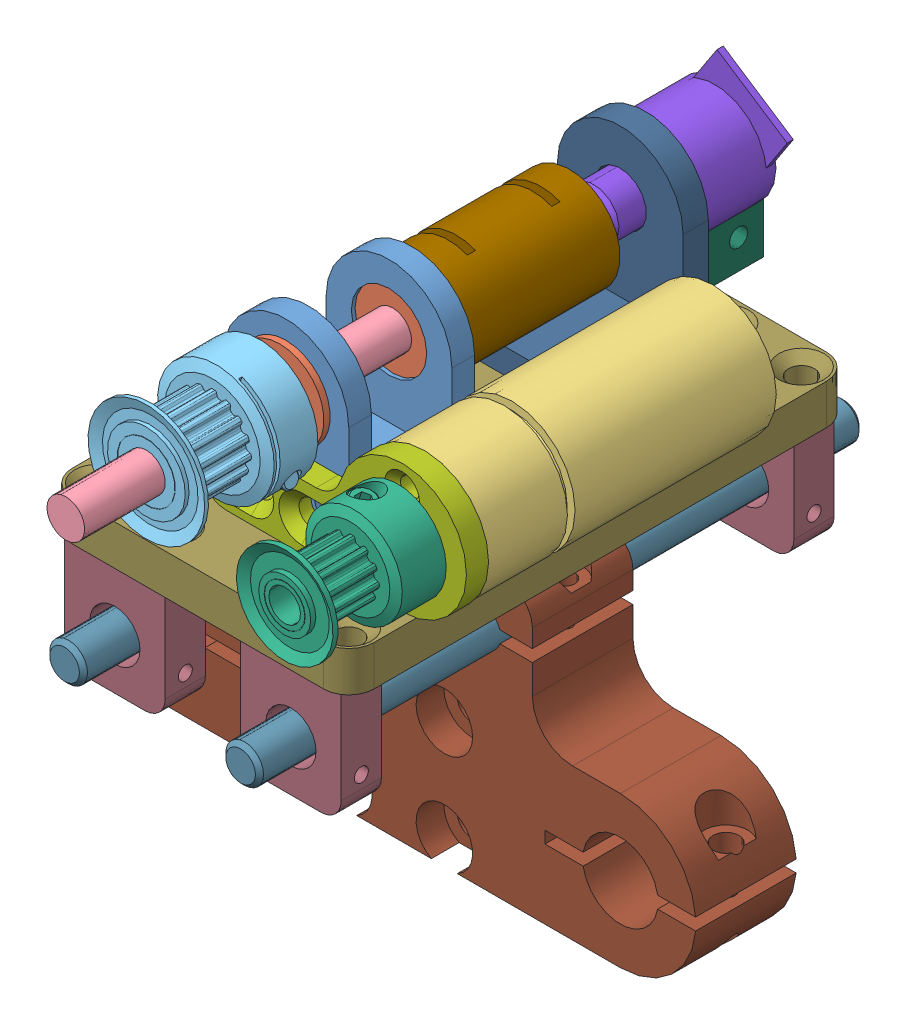
SolidWorks assembly wrist-yaw-joint, configuration Default. Lengths in mm.
Overall size (76.14 66.56 105.58).
22 component instances, 17 part files, 53 mates.
Components (placement in the parent):
- n05-headyoke-1: n05-headyoke [Default] at origin size (15.88 21.91 15.88)
- p1875bearing-57155K319-MCM-1: p1875bearing-57155K319-MCM [Default] at (0 13.97 5.5499) x (0 0 -1) z (0 -1 0) size (3.17 11.18 11.18)
- p1875bearing-57155K319-MCM-2: p1875bearing-57155K319-MCM [Default] at (0 13.97 -5.5499) x (0 0 1) z (0 -1 0) size (3.17 11.18 11.18)
- MAXON-AMAX16-110049-110323-1: MAXON-AMAX16-110049-110323 [Default] at (17.4625 8.128 -28.5125) x (0 0 -1) z (1 0 0) size (48.2 16 16)
- n06-p1875shaft-1: n06-p1875shaft [Default] at (0 13.97 -15.0749) size (4.76 4.76 50.8)
- a_6d16-016df2506-p1875bore-16teeth-1: a_6d16-016df2506-p1875bore-16teeth [Default] at (0 13.97 17.218) x (0.167713 -0.985836 0) z (0 0 -1) size (14.73 14.73 14.29)
- a_6d16m012df6003-3mm-bored-to-4mm-1: a_6d16m012df6003-3mm-bored-to-4mm [Default] at (17.4625 8.128 17.2524) x (-0.948708 0.316155 0) z (0 0 -1) size (12.2 12.2 14.3)
- a_6n16-015df1206-2: a_6n16-015df1206 [Default] at (-14.2838 6.954 15.9813) x (0.986257 0.164531 -0.015045) z (-0.021924 0.040076 -0.998956) size (14.1 14.1 11.13) (hidden)
- n09-motor-holder-1: n09-motor-holder [Default] at (17.4625 8.128 7.9375) size (33.53 16.26 2.79)
- POT-eti-sys-EUP125-1: POT-eti-sys-EUP125 [Default] at (0 13.97 -47.4345) x (0 0 -1) z (0.836462 -0.548026 0) size (30.58 15.39 13)
- 000_helical-coupling-6208K53-MCM-1: 000_helical-coupling-6208K53-MCM [Default] at (0 13.97 -18.3769) size (12.7 12.7 19.05)
- n10-potholder-1: n10-potholder [Default] at (0 0 -29.5148) size (15.88 21.91 15.88)
- w04-shaft-hold-bottom-2: w04-shaft-hold-bottom [Default] at (0 -32.0675 -5.715) x (1 0 0) z (0 1 0) size (76.14 12.7 34.92)
- w06-plate-1: w06-plate [Default] at (0 0 -12.7) x (1 0 0) z (0 -1 0) size (38.1 63.5 5.08)
- w07-clamp-1: w07-clamp [Default] at (11.1125 -13.0175 -43.815) size (12.7 14.29 5.08)
- w07-clamp-2: w07-clamp [Default] at (11.1125 -13.0175 13.335) size (12.7 14.29 5.08)
- w07-clamp-3: w07-clamp [Default] at (-11.1125 -13.0175 -43.815) size (12.7 14.29 5.08)
- w07-clamp-4: w07-clamp [Default] at (-11.1125 -13.0175 13.335) size (12.7 14.29 5.08)
- w08-p1875shaft-1: w08-p1875shaft [Default] at (-11.1125 -13.0175 -51.435) size (4.76 4.76 76.2)
- w08-p1875shaft-2: w08-p1875shaft [Default] at (11.1125 -13.0175 -51.435) size (4.76 4.76 76.2)
- 000_Bourns_linearpot_body_3048seriesRevC-dp2-1: 000_Bourns_linearpot_body_3048seriesRevC-dp2 [Default] at (-23.8125 -10.668 -38.1) x (0 0 -1) z (0 -1 0) size (31.75 6.35 8.28)
- y18-pot-end-holder-1: y18-pot-end-holder [Default] at (-20.6375 -18.8595 -12.065) x (0 0 1) z (-1 0 0) size (10.16 9.53 6.35)
Mates (geometry in assembly coordinates):
- Coincident1: coincident anti-aligned: plane of n05-headyoke-1 through (0 13.97 7.9375) normal (0 0 1); plane of p1875bearing-57155K319-MCM-1 through (4.7625 13.97 7.9375) normal (0 0 -1)
- Coincident2: coincident anti-aligned: plane of n05-headyoke-1 through (0 13.97 -7.9375) normal (0 0 -1); plane of p1875bearing-57155K319-MCM-2 through (-4.7625 13.97 -7.9375) normal (0 0 1)
- Concentric1: concentric anti-aligned: cylinder of n05-headyoke-1; cylinder of p1875bearing-57155K319-MCM-2
- Concentric2: concentric aligned: cylinder of n05-headyoke-1; cylinder of p1875bearing-57155K319-MCM-1
- Coincident3: coincident anti-aligned: plane of p1875bearing-57155K319-MCM-1 through (0 13.97 5.5499) normal (1 0 0); plane of p1875bearing-57155K319-MCM-2 through (0 13.97 -5.5499) normal (-1 0 0)
- Parallel1: parallel aligned: plane of n05-headyoke-1 through (7.9375 0 7.9375) normal (1 0 0); plane of p1875bearing-57155K319-MCM-1 through (0 13.97 5.5499) normal (1 0 0)
- Concentric3: concentric anti-aligned: cylinder of p1875bearing-57155K319-MCM-2; cylinder of n06-p1875shaft-1
- Distance1: distance = 6.35 mm aligned: plane of p1875bearing-57155K319-MCM-2 through (-5.588 13.97 -8.7249) normal (0 0 -1); plane of n06-p1875shaft-1 through (0 13.97 -15.0749) normal (0 0 -1)
- Concentric4: concentric aligned: cylinder of n06-p1875shaft-1; cylinder of a_6d16-016df2506-p1875bore-16teeth-1
- Distance2: distance = 2.54 mm anti-aligned: plane of p1875bearing-57155K319-MCM-1 through (5.588 13.97 8.7249) normal (0 0 1); plane of a_6d16-016df2506-p1875bore-16teeth-1 through (-7.2617 12.7346 11.2649) normal (0 0 -1)
- Coincident7: coincident aligned: plane of n05-headyoke-1 through (0 13.97 7.9375) normal (0 0 1); plane of MAXON-AMAX16-110049-110323-1 through (17.4625 16.128 7.9375) normal (0 0 1)
- Concentric5: concentric aligned: cylinder of MAXON-AMAX16-110049-110323-1; cylinder of a_6d16m012df6003-3mm-bored-to-4mm-1
- Coincident8: coincident aligned: plane of a_6d16-016df2506-p1875bore-16teeth-1 through (0 13.97 25.5524) normal (0 0 1); plane of a_6d16m012df6003-3mm-bored-to-4mm-1 through (17.4625 8.128 25.5524) normal (0 0 1)
- Concentric6: concentric aligned: cylinder of MAXON-AMAX16-110049-110323-1; cylinder of n09-motor-holder-1
- Coincident9: coincident anti-aligned: plane of MAXON-AMAX16-110049-110323-1 through (17.4625 16.128 7.9375) normal (0 0 1); plane of n09-motor-holder-1 through (17.4625 8.128 7.9375) normal (0 0 -1)
- Concentric7: concentric anti-aligned: cylinder of n05-headyoke-1; cylinder of n09-motor-holder-1
- Concentric8: concentric anti-aligned: cylinder of n05-headyoke-1; cylinder of n09-motor-holder-1
- Concentric9: concentric aligned: cylinder of MAXON-AMAX16-110049-110323-1; cylinder of n09-motor-holder-1
- Distance3: distance = 0.127 mm anti-aligned: plane of p1875bearing-57155K319-MCM-2; plane of 000_helical-coupling-6208K53-MCM-1 through (0 13.97 -8.8519) normal (0 0 1)
- Concentric10: concentric aligned: cylinder of n06-p1875shaft-1; cylinder of 000_helical-coupling-6208K53-MCM-1
- Distance4: distance = 2.54 mm anti-aligned: plane of POT-eti-sys-EUP125-1 through (1.74 16.6258 -30.4419) normal (0 0 1); plane of 000_helical-coupling-6208K53-MCM-1 through (0 13.97 -27.9019) normal (0 0 -1)
- Concentric11: concentric aligned: cylinder of POT-eti-sys-EUP125-1; cylinder of 000_helical-coupling-6208K53-MCM-1
- Coincident10: coincident anti-aligned: plane of POT-eti-sys-EUP125-1 through (3.5635 19.409 -37.4523) normal (0 0 1); plane of n10-potholder-1 through (0 13.97 -37.4523) normal (0 0 -1)
- Concentric12: concentric aligned: cylinder of POT-eti-sys-EUP125-1; cylinder of n10-potholder-1
- Coincident11: coincident aligned: plane of n05-headyoke-1 through (7.9375 0 7.9375) normal (0 -1 0); plane of n10-potholder-1 through (7.9375 0 -21.5773) normal (0 -1 0)
- Concentric13: concentric aligned: cylinder of n05-headyoke-1; cylinder of w06-plate-1
- Concentric14: concentric aligned: cylinder of n05-headyoke-1; cylinder of w06-plate-1
- Coincident12: coincident anti-aligned: plane of n05-headyoke-1; plane of w06-plate-1 through (-19.05 0 -44.45) normal (0 1 0)
- Concentric15: concentric aligned: cylinder of w06-plate-1; cylinder of w07-clamp-3
- Concentric16: concentric aligned: cylinder of w06-plate-1; cylinder of w07-clamp-3
- Concentric17: concentric aligned: cylinder of w06-plate-1; cylinder of w07-clamp-1
- Concentric18: concentric aligned: cylinder of w06-plate-1; cylinder of w07-clamp-1
- Concentric19: concentric aligned: cylinder of w06-plate-1; cylinder of w07-clamp-4
- Concentric20: concentric aligned: cylinder of w06-plate-1; cylinder of w07-clamp-4
- Concentric21: concentric aligned: cylinder of w06-plate-1; cylinder of w07-clamp-2
- Concentric22: concentric aligned: cylinder of w06-plate-1; cylinder of w07-clamp-2
- Coincident13: coincident anti-aligned: plane of w06-plate-1 through (-19.05 -5.08 -44.45) normal (0 -1 0); plane of w07-clamp-2 through (4.7625 -5.08 18.415) normal (0 1 0)
- Coincident14: coincident anti-aligned: plane of w06-plate-1 through (-19.05 -5.08 -44.45) normal (0 -1 0); plane of w07-clamp-1 through (4.7625 -5.08 -38.735) normal (0 1 0)
- Coincident15: coincident anti-aligned: plane of w06-plate-1 through (-19.05 -5.08 -44.45) normal (0 -1 0); plane of w07-clamp-3 through (-17.4625 -5.08 -38.735) normal (0 1 0)
- Coincident16: coincident anti-aligned: plane of w06-plate-1 through (-19.05 -5.08 -44.45) normal (0 -1 0); plane of w07-clamp-4 through (-17.4625 -5.08 18.415) normal (0 1 0)
- Concentric23: concentric aligned: cylinder of w04-shaft-hold-bottom-2; cylinder of w08-p1875shaft-2
- Coincident17: coincident aligned: plane of w08-p1875shaft-1 through (-11.1125 -13.0175 24.765) normal (0 0 1); plane of w08-p1875shaft-2 through (11.1125 -13.0175 24.765) normal (0 0 1)
- Concentric24: concentric aligned: cylinder of w07-clamp-2; cylinder of w08-p1875shaft-2
- Concentric25: concentric aligned: cylinder of w04-shaft-hold-bottom-2; cylinder of w08-p1875shaft-1
- Concentric26: concentric aligned: cylinder of w07-clamp-4; cylinder of w08-p1875shaft-1
- Distance5: distance = 6.35 mm aligned: plane of w07-clamp-2 through (4.7625 -5.08 18.415) normal (0 0 1); plane of w08-p1875shaft-2 through (11.1125 -13.0175 24.765) normal (0 0 1)
- Distance6: distance = 19.05 mm anti-aligned: plane of w04-shaft-hold-bottom-2 through (-28.575 -32.0675 -5.715) normal (0 0 1); plane of w07-clamp-2 through (4.7625 -5.08 13.335) normal (0 0 -1)
- Concentric27: concentric aligned: cylinder of w07-clamp-3; cylinder of 000_Bourns_linearpot_body_3048seriesRevC-dp2-1
- Parallel2: parallel aligned: plane of w06-plate-1; plane of 000_Bourns_linearpot_body_3048seriesRevC-dp2-1 through (-17.4625 -10.668 -38.1) normal (0 1 0)
- Coincident19: coincident anti-aligned: plane of w07-clamp-3; plane of 000_Bourns_linearpot_body_3048seriesRevC-dp2-1 through (-17.4625 -18.9484 -38.1) normal (1 0 0)
- Coincident20: coincident anti-aligned: plane of w04-shaft-hold-bottom-2 through (-17.4625 -22.5425 32.6487) normal (-1 0 0); plane of y18-pot-end-holder-1 through (-17.4625 -9.3345 -17.145) normal (1 0 0)
- Concentric28: concentric aligned: cylinder of w04-shaft-hold-bottom-2; cylinder of y18-pot-end-holder-1
- Parallel3: parallel aligned: plane of w04-shaft-hold-bottom-2 through (-21.478 -13.7795 -5.715) normal (0 1 0); plane of y18-pot-end-holder-1 through (-23.8125 -9.3345 -17.145) normal (0 1 0)
